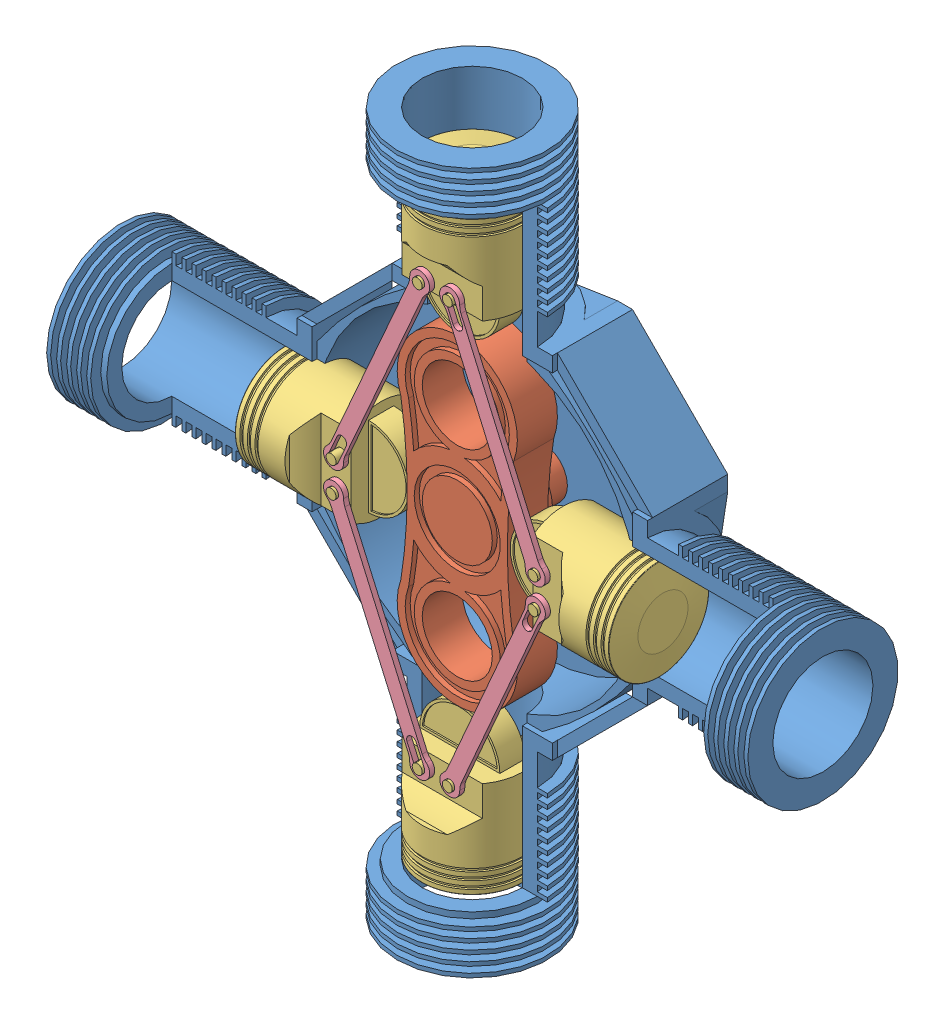
SolidWorks assembly V4 engine assembly, configuration Default. Lengths in mm.
Overall size (700 700 190).
10 component instances, 4 part files, 23 mates.
Components (placement in the parent):
- casing-1: casing [Default] at origin size (700 700 155)
- cam-1: cam [Default] at (-0.0028 -100 95) x (-1 0.000028 0) z (0 0 1) size (120 320 130)
- piston-1: piston [Default] at (0 200 80) size (100 139.99 100)
- piston-2: piston [Default] at (-91.0197 0 80) x (0 -1 0) z (0 0 -1) size (100 139.99 100)
- connecting rod-1: connecting rod [Default] at (-15 210 112.5) x (0.403602 0.914935 0) z (0 0 1) size (233.13 20 5)
- connecting rod-2: connecting rod [Default] at (-101.0197 -15 112.5) x (-0.403602 0.914935 0) z (0 0 1) size (233.13 20 5)
- piston-3: piston [Default] at (0 -200 80) x (-1 0 0) z (0 0 1) size (100 139.99 100)
- connecting rod-3: connecting rod [Default] at (15 -210 112.5) x (-0.401133 -0.91602 0) z (0 0 1) size (233.13 20 5)
- piston-4: piston [Default] at (90.3922 0 80) x (0 1 0) z (0 0 -1) size (100 139.99 100)
- connecting rod-4: connecting rod [Default] at (100.3922 15 112.5) x (0.401133 -0.91602 0) z (0 0 1) size (233.13 20 5)
Mates (geometry in assembly coordinates):
- Coincident1: coordinate: point of casing-1
- Concentric1: concentric anti-aligned: circle of casing-1; circle of cam-1
- Distance2: distance = 35 mm aligned: plane of cam-1 through (0 0 -35) normal (0 0 -1); plane of casing-1 through (0 0 0) normal (0 0 -1)
- Concentric2: concentric aligned: circle of casing-1; circle of piston-1
- Parallel1: parallel aligned: plane of cam-1 through (274.9986 -50.0078 95) normal (0 0 1); plane of piston-1 through (0 200 91) normal (0 0 1)
- Concentric4: concentric aligned: circle of casing-1; circle of piston-2
- Parallel2: parallel aligned: plane of casing-1 through (0 0 10) normal (0 0 1); plane of piston-2 through (-91.0197 0 91) normal (0 0 1)
- Concentric5: concentric anti-aligned: cylinder of piston-1 through (-15 210 40) axis (0 0 1) radius 5; cylinder of connecting rod-1 through (-15 210 117.5) axis (0 0 -1) radius 5
- Width1: width aligned: plane of piston-1 through (-50 200 110) normal (0 0 1); plane of piston-1 through (-15 210 120) normal (0 0 1); plane of connecting rod-1 through (-39.9842 209.1108 117.5) normal (0 0 1); plane of connecting rod-1 through (-39.9842 209.1108 112.5) normal (0 0 -1)
- Tangent6: tangent anti-aligned: cylinder of piston-2 through (-101.0197 15 120) axis (0 0 -1) radius 5; plane of connecting rod-1 through (-105.5944 17.018 117.5) normal (0.914935 -0.403602 0)
- Concentric6: concentric aligned: circle of casing-1; circle of piston-3
- Parallel3: parallel aligned: plane of casing-1 through (0 0 10) normal (0 0 1); plane of piston-3 through (0 -200 91) normal (0 0 1)
- Width4: width aligned: plane of piston-2 through (-91.0197 50 110) normal (0 0 1); plane of piston-2 through (-101.0197 -15 120) normal (0 0 1); plane of connecting rod-2 through (-117.2076 -34.0513 117.5) normal (0 0 1); plane of connecting rod-2 through (-117.2076 -34.0513 112.5) normal (0 0 -1)
- Concentric10: concentric aligned: circle of piston-2; circle of connecting rod-2
- Tangent13: tangent anti-aligned: plane of connecting rod-2 through (-10.4253 -207.982 117.5) normal (-0.914935 -0.403602 0); cylinder of piston-3 through (-15 -210 40) axis (0 0 1) radius 5
- Concentric11: concentric aligned: circle of casing-1; circle of piston-4
- Parallel4: parallel aligned: plane of casing-1 through (0 0 10) normal (0 0 1); plane of piston-4 through (90.3922 0 91) normal (0 0 1)
- Width5: width aligned: plane of piston-4 through (90.3922 -50 110) normal (0 0 1); plane of connecting rod-4 through (100.3922 15 120) normal (0 0 1); plane of piston-4 through (116.6314 34.0076 117.5) normal (0 0 1); plane of connecting rod-4 through (116.6314 34.0076 112.5) normal (0 0 -1)
- Concentric12: concentric anti-aligned: circle of piston-4; cylinder of connecting rod-4 through (100.3922 15 117.5) axis (0 0 -1) radius 5
- Tangent15: tangent anti-aligned: cylinder of piston-1 through (15 210 40) axis (0 0 1) radius 5; plane of connecting rod-4 through (19.4788 212.237 117.5) normal (-0.91602 -0.401133 0)
- Width6: width aligned: plane of piston-3 through (50 -200 110) normal (0 0 1); plane of connecting rod-3 through (15 -210 120) normal (0 0 1); plane of piston-3 through (39.9817 -209.0434 117.5) normal (0 0 1); plane of connecting rod-3 through (39.9817 -209.0434 112.5) normal (0 0 -1)
- Concentric13: concentric aligned: circle of piston-3; circle of connecting rod-3
- Tangent16: tangent anti-aligned: plane of connecting rod-3 through (105.0736 -16.7744 117.5) normal (-0.91602 0.401133 0); cylinder of piston-4 through (100.3922 -15 120) axis (0 0 -1) radius 5
